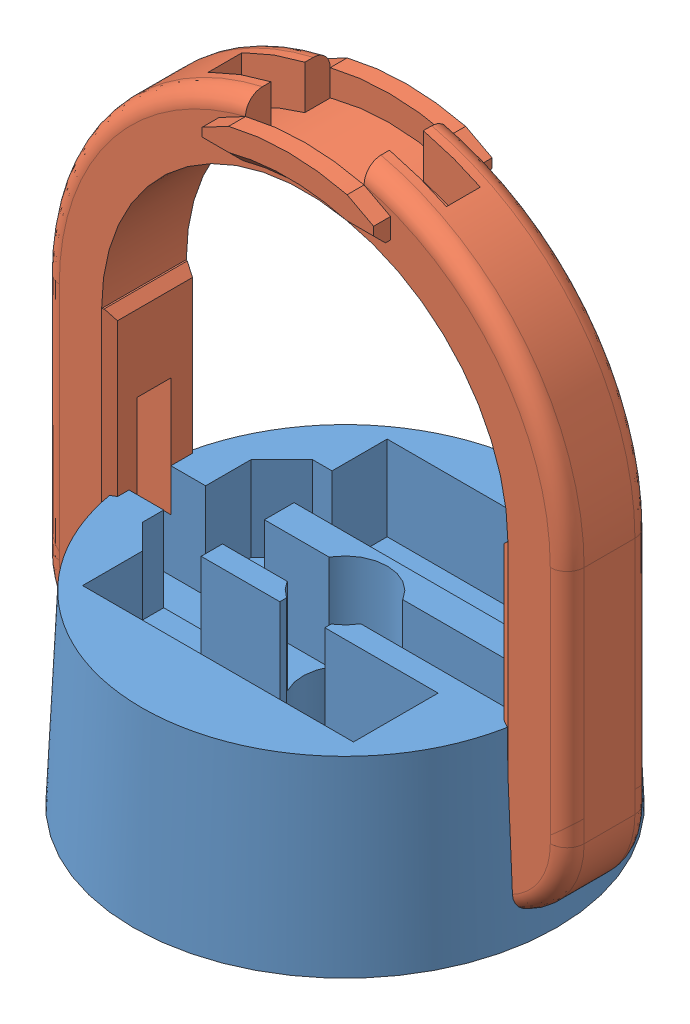
SolidWorks assembly Ring_part, configuration 默认. Lengths in mm.
Overall size (31 35.66 25).
2 component instances, 2 part files, 3 mates.
Components (placement in the parent):
- ring2-1: ring2 [默认] at (15.4172 11.6746 10.1165) size (25 11 25)
- ring3-1: ring3 [默认] at (15.304 32.1697 9.8781) x (-1 0 0) z (0 1 0) size (31 7 34.27)
Mates (geometry in assembly coordinates):
- 平行1: parallel: plane of ring2-1 through (15.4172 17.6746 7.1255) normal (0 0 -1); plane of ring3-1 through (15.304 32.1697 7.3781) normal (0 0 -1)
- 重合8: coincident: plane of ring2-1 through (-4.5828 17.0476 8.8781) normal (0 0 1); plane of ring3-1 through (15.304 32.1697 8.8781) normal (0 0 1)
- 平行3: parallel: plane of ring2-1 through (15.4172 22.6746 10.1165) normal (0 1 0); plane of ring3-1 through (15.304 27.1697 9.8781) normal (0 -1 0)
